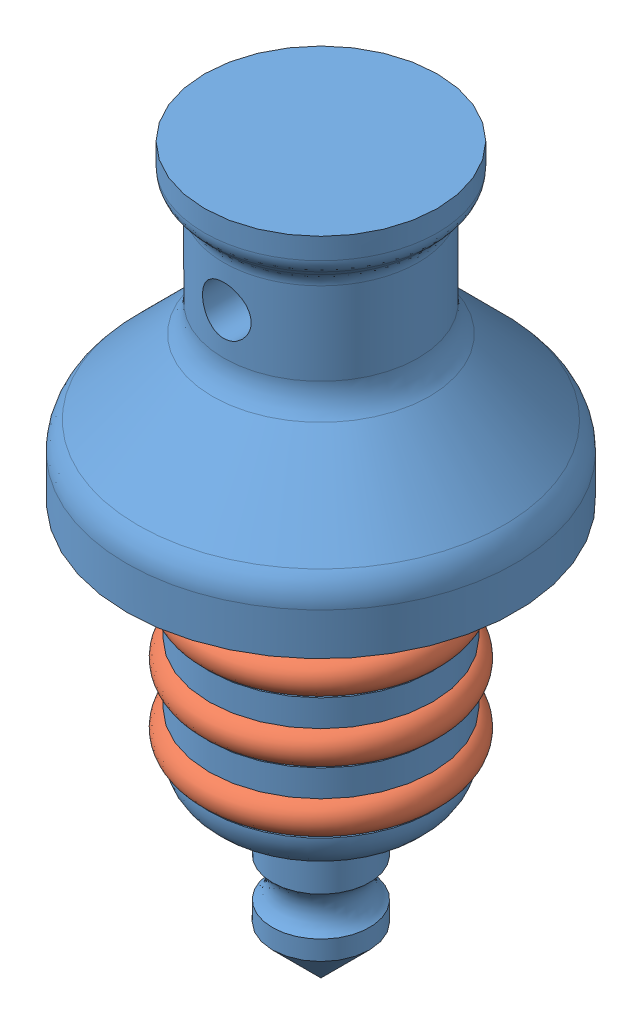
SolidWorks assembly Normbuchse-Stopfen, configuration Standard. Lengths in mm.
Overall size (20 37.3 20).
5 component instances, 3 part files, 8 mates.
Components (placement in the parent):
- Normbuchse-Stopfen-1: Normbuchse-Stopfen [Standard] at (-113.3021 -10.0814 0) size (20 37.3 20)
- O-Ring-12mm-1: O-Ring-12mm [Standard] at (-113.3021 -0.9564 0) x (0.999693 0 -0.024773) z (0 -1 0) size (12.5 12.5 1.75)
- O-Ring-15mm-1: O-Ring-15mm [Standard] at (-113.3021 2.9186 0) x (1 0 0) z (0 -1 0) size (14.5 14.5 2)
- O-Ring-12mm-2: O-Ring-12mm [Standard] at (-113.3021 -4.0889 0) x (0.998627 0 -0.05238) z (0 -1 0) size (12.5 12.5 1.75)
- O-Ring-12mm-3: O-Ring-12mm [Standard] at (-113.3021 -7.2064 0) x (-0.982926 0 0.184002) z (0 -1 0) size (12.5 12.5 1.75)
Mates (geometry in assembly coordinates):
- Konzentrisch1: concentric anti-aligned: circle of Normbuchse-Stopfen-1; line of O-Ring-12mm-3 through (-113.3021 -7.2064 0) axis (0 1 0)
- Abstand1: distance = 2.875 mm: point of O-Ring-12mm-3; plane of Normbuchse-Stopfen-1 through (-115.8021 -10.0814 0) normal (0 -1 0)
- Konzentrisch2: concentric anti-aligned: circle of Normbuchse-Stopfen-1; line of O-Ring-12mm-2 through (-113.3021 -4.0889 0) axis (0 1 0)
- Konzentrisch3: concentric anti-aligned: circle of Normbuchse-Stopfen-1; line of O-Ring-12mm-1 through (-113.3021 -0.9564 0) axis (0 1 0)
- Abstand2: distance = 9.125 mm: point of O-Ring-12mm-1; plane of Normbuchse-Stopfen-1 through (-115.8021 -10.0814 0) normal (0 -1 0)
- Abstand3: distance = 5.9925 mm: point of O-Ring-12mm-2; plane of Normbuchse-Stopfen-1 through (-115.8021 -10.0814 0) normal (0 -1 0)
- Konzentrisch4: concentric anti-aligned: circle of Normbuchse-Stopfen-1; line of O-Ring-15mm-1 through (-113.3021 2.9186 0) axis (0 1 0)
- Abstand4: distance = 13 mm: point of O-Ring-15mm-1; plane of Normbuchse-Stopfen-1 through (-115.8021 -10.0814 0) normal (0 -1 0)
